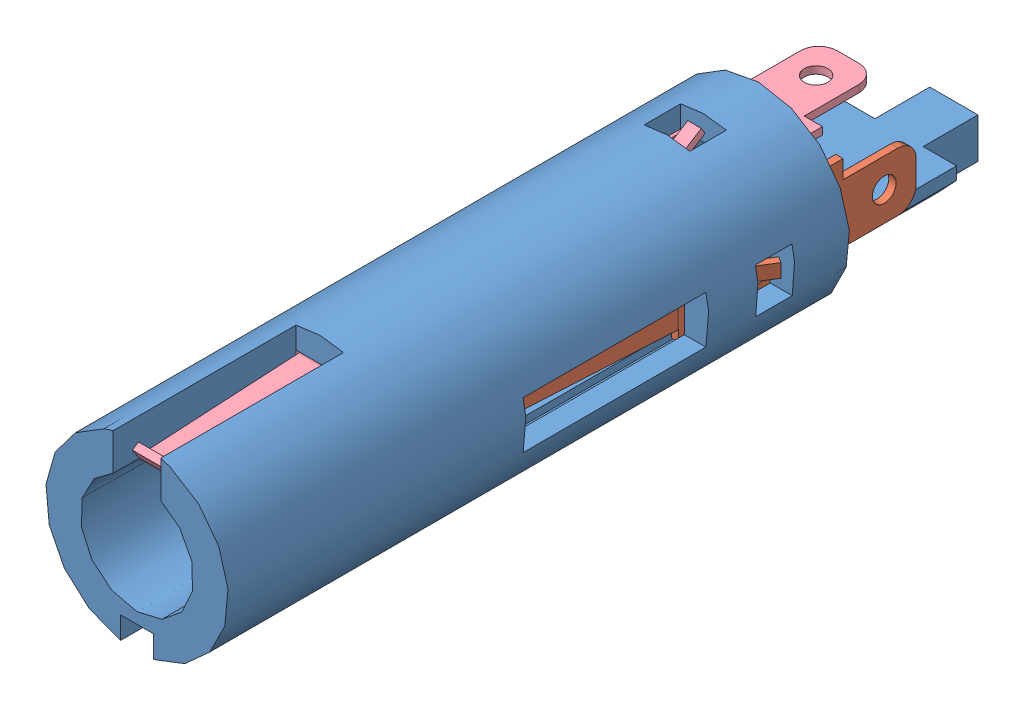
SolidWorks assembly t12-connector, configuration Default. Lengths in mm.
Overall size (10 9.92 44.7).
4 component instances, 4 part files, 0 mates.
Components (placement in the parent):
- Imported-1: Imported [默认] at origin size (10 9.92 44.7)
- Imported_2-1: Imported_2 [默认] at (4.64 0.09 -1) x (0 0 1) z (-1 0 0) size (22.42 5.2 1.87)
- Imported_3-1: Imported_3 [默认] at (-3.64 -0.09 -5) x (0 0 1) z (1 0 0) size (31.67 5.2 1.86)
- Imported_4-1: Imported_4 [默认] at (-0.09 3.64 -5) x (0 0 1) z (0 -1 0) size (38.17 5.2 1.86)
